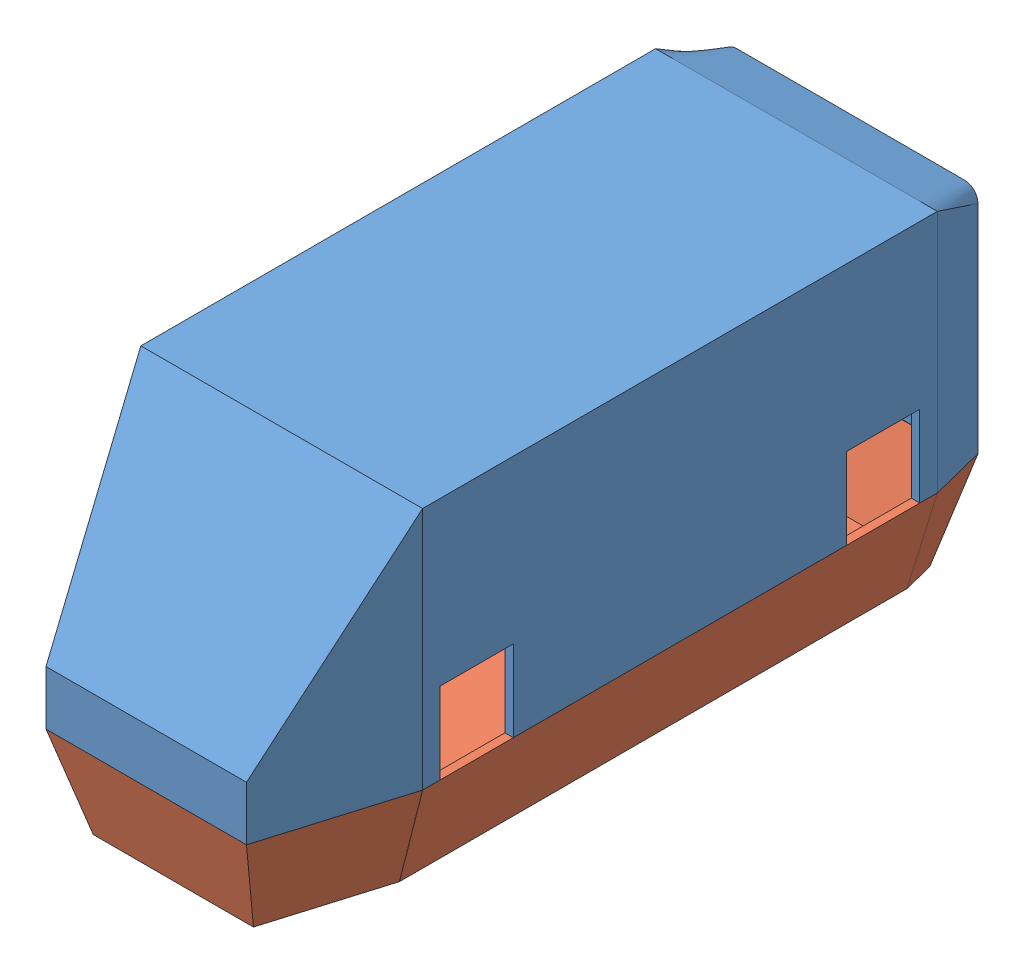
SolidWorks assembly Assem1, configuration Default. Lengths in mm.
Overall size (104 125 260.05).
2 component instances, 2 part files, 3 mates.
Components (placement in the parent):
- Cover-1: Cover [Default] at (140.7777 133.2706 116.4034) size (104 90 260.05)
- LowerCover-1: LowerCover [Default] at (140.7777 168.2706 116.4034) x (1 0 0) z (0 -1 0) size (104 260 35)
Mates (geometry in assembly coordinates):
- Coincident1: coincident anti-aligned: line of Cover-1 through (103.7777 133.2706 261.4034) axis (1 0 0); line of LowerCover-1 through (177.7777 133.2706 261.4034) axis (-1 0 0)
- Coincident2: coincident anti-aligned: line of Cover-1 through (187.7777 133.2706 1.4034) axis (-1 0 0); line of LowerCover-1 through (93.7777 133.2706 1.4034) axis (1 0 0)
- Coincident3: coincident anti-aligned: line of Cover-1 through (192.7777 133.2706 177.9034) axis (0 0 -1); line of LowerCover-1 through (192.7777 133.2706 21.4034) axis (0 0 1)
